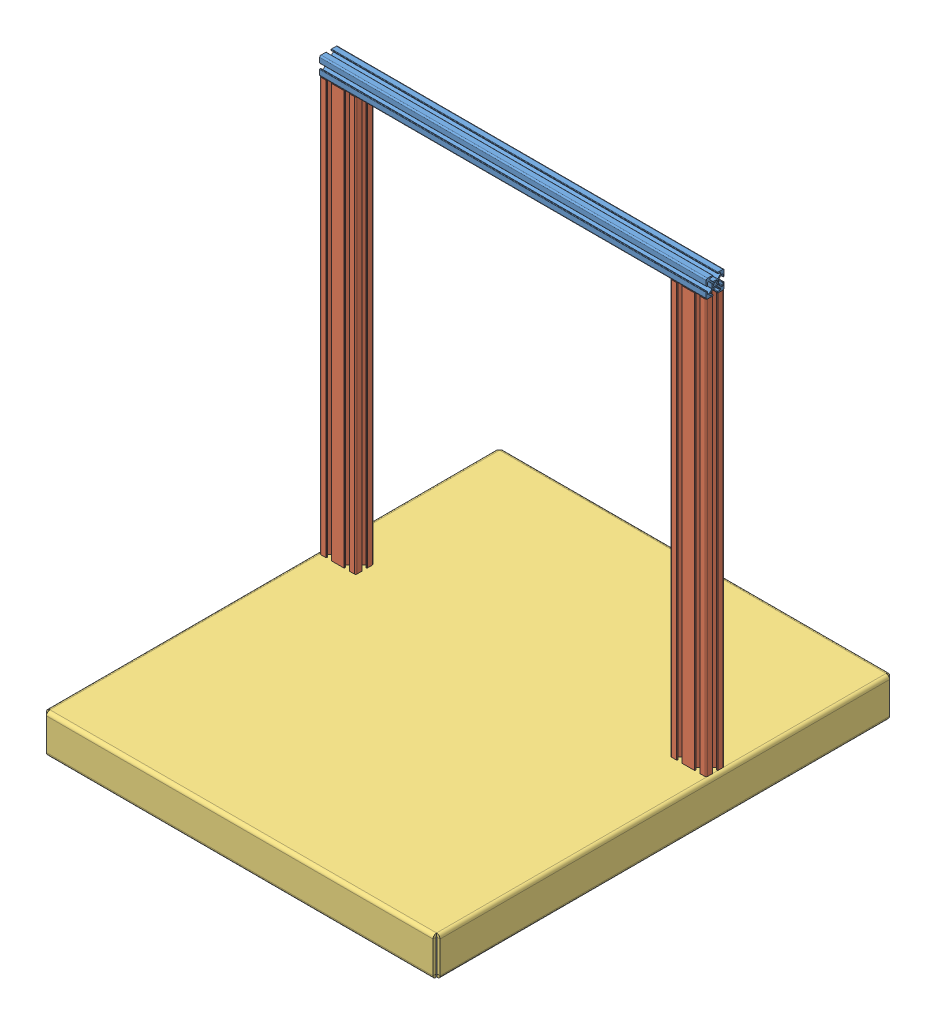
SolidWorks assembly Innobot Jumbo Frame, configuration Default. Lengths in mm.
Overall size (437.82 523.17 507.82).
4 component instances, 3 part files, 9 mates.
Components (placement in the parent):
- TopCeiling-1: TopCeiling [20-2020-BLACK] at (-74.5195 587.4544 205.3802) x (0 0 -1) z (1 0 0) size (20 20 430)
- UprightSides-1: UprightSides [20-2040-BLACK] at (-84.5195 117.4544 205.3802) x (1 0 0) z (0 -1 0) size (40 20 460)
- UprightSides-2: UprightSides [20-2040-BLACK] at (-474.5195 117.4544 205.3802) x (1 0 0) z (0 -1 0) size (40 20 460)
- printer_Cover-1: printer_Cover [Default] at (-81.1195 117.4544 131.1302) size (437.82 43.17 507.82)
Mates (geometry in assembly coordinates):
- Coincident17: coincident anti-aligned: plane of TopCeiling-1 through (-504.5195 577.4544 202.2422) normal (0 -1 0); plane of UprightSides-2 through (-496.9034 577.4544 201.2172) normal (0 1 0)
- Coincident18: coincident aligned: plane of TopCeiling-1 through (-504.5195 590.5924 215.3802) normal (0 0 1); plane of UprightSides-2 through (-477.6575 577.4544 215.3802) normal (0 0 1)
- Coincident19: coincident aligned: plane of TopCeiling-1 through (-504.5195 590.5924 195.8882) normal (-1 0 0); plane of UprightSides-2 through (-504.5195 577.4544 213.8802) normal (-1 0 0)
- Distance1: distance = 180 mm aligned: plane of UprightSides-1 through (-101.3815 577.4544 195.3802) normal (0 0 -1); line of printer_Cover-1 through (-74.5195 117.4544 15.3802) axis (-1 0 0)
- Coincident25: coincident anti-aligned: plane of UprightSides-1 through (-106.9034 117.4544 201.2172) normal (0 -1 0); plane of printer_Cover-1 through (-81.1195 117.4544 131.1302) normal (0 1 0)
- Coincident27: coincident anti-aligned: line of UprightSides-1 through (-74.5195 117.4544 208.5182) axis (0 0 1); line of printer_Cover-1 through (-74.5195 117.4544 515.3802) axis (0 0 -1)
- Coincident28: coincident aligned: plane of TopCeiling-1 through (-504.5195 584.3164 215.3802) normal (0 0 1); plane of UprightSides-1 through (-87.6575 577.4544 215.3802) normal (0 0 1)
- Coincident30: coincident anti-aligned: plane of TopCeiling-1 through (-504.5195 577.4544 202.2422) normal (0 -1 0); plane of UprightSides-1 through (-106.9034 577.4544 201.2172) normal (0 1 0)
- Coincident31: coincident aligned: plane of TopCeiling-1 through (-74.5195 590.5924 195.8882) normal (1 0 0); plane of UprightSides-1 through (-74.5195 577.4544 196.8802) normal (1 0 0)
